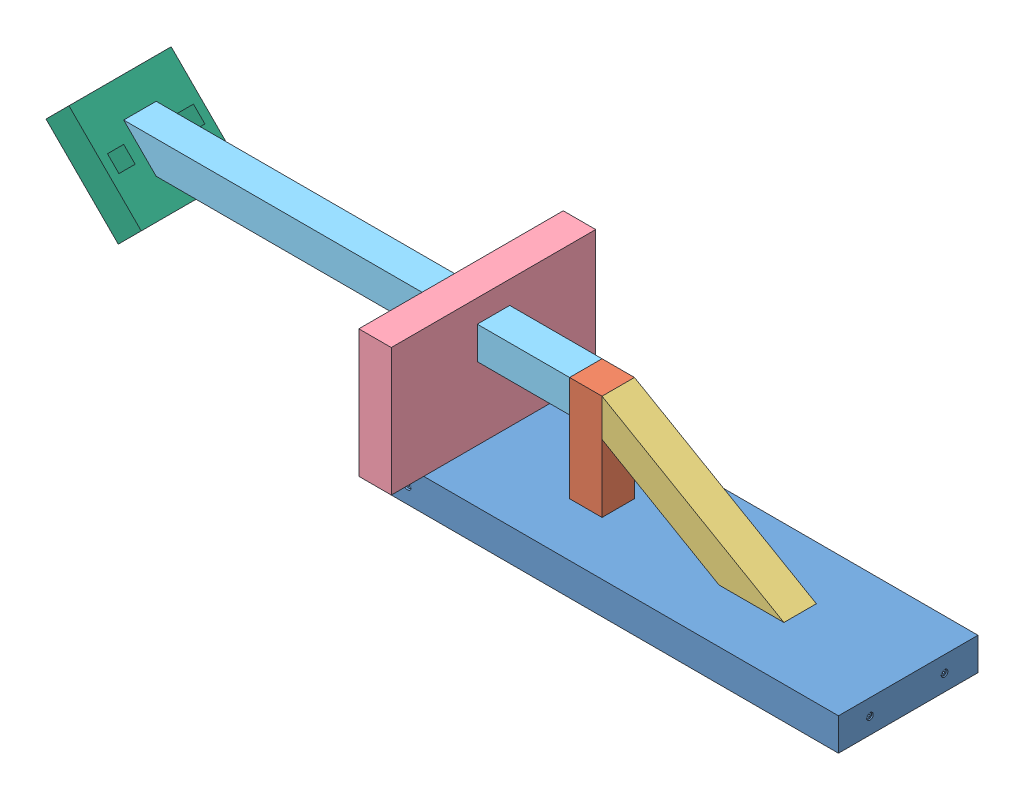
SolidWorks assembly mounting, configuration Default. Lengths in mm.
Overall size (634.84 125.4 160).
11 component instances, 7 part files, 25 mates.
Components (placement in the parent):
- small side with mount-1: small side with mount [Default] at (84.4409 129.8195 235.0864) size (350 25.4 109.2)
- a side of triangle-1: a side of triangle [Default] at (32.483 196.3149 235.0864) x (0 1 0) z (0 0 1) size (82.19 25.4 25.4)
- hypothonuse-2: hypothonuse [Default] at (174.8409 155.2195 235.0864) x (0 0 1) z (0 -1 0) size (25.4 142.36 82.19)
- antenna protector with mount-1: antenna protector with mount [Default] at (-90.5591 205.2195 235.0864) x (0 -1 0) z (0 0 1) size (100 25.4 160)
- tall mount-1: tall mount [Default] at (-167.402 224.7099 235.0864) x (0 -1 0) z (0 0 -1) size (25.4 348.97 25.4)
- mount top-1: mount top [Default] at (-329.154 224.6769 235.0844) x (0 0 1) z (0.707107 -0.707107 0) size (80 25.4 80)
- 90031A117_PHILLIPS FLAT HEAD SCREWS FOR WOOD-1: 90031A117_PHILLIPS FLAT HEAD SCREWS FOR WOOD [90031A117] at (-335.8892 217.9417 235.0844) x (0.707107 0.707107 0) z (0 0 1) size (31.75 5.71 5.71)
- 90031A117_PHILLIPS FLAT HEAD SCREWS FOR WOOD-2: 90031A117_PHILLIPS FLAT HEAD SCREWS FOR WOOD [90031A117] at (19.6301 145.6945 235.0326) x (0 1 0) z (-0.546944 0 0.837169) size (31.75 5.71 5.71)
- 90031A117_PHILLIPS FLAT HEAD SCREWS FOR WOOD-3: 90031A117_PHILLIPS FLAT HEAD SCREWS FOR WOOD [90031A117] at (149.6575 145.6945 235.1226) x (0 1 0) z (-0.546944 0 0.837169) size (31.75 5.71 5.71)
- 90031A117_PHILLIPS FLAT HEAD SCREWS FOR WOOD-6: 90031A117_PHILLIPS FLAT HEAD SCREWS FOR WOOD [90031A117] at (-77.8591 145.6945 264.2864) x (0 1 0) z (-0.546944 0 0.837169) size (31.75 5.71 5.71)
- 90031A117_PHILLIPS FLAT HEAD SCREWS FOR WOOD-7: 90031A117_PHILLIPS FLAT HEAD SCREWS FOR WOOD [90031A117] at (-77.8591 145.6945 205.8864) x (0 1 0) z (-0.546944 0 0.837169) size (31.75 5.71 5.71)
Mates (geometry in assembly coordinates):
- Concentric4: concentric aligned: cylinder of small side with mount-1 through (149.4409 129.8195 235.0864) axis (0 -1 0) radius 0.889; cylinder of hypothonuse-2 through (149.4409 155.2195 235.0864) axis (0 -1 0) radius 0.5956
- Coincident6: coincident anti-aligned: plane of small side with mount-1 through (84.4409 155.2195 235.0864) normal (0 1 0); plane of hypothonuse-2 through (174.8409 155.2195 247.7864) normal (0 -1 0)
- Parallel5: parallel aligned: plane of small side with mount-1 through (-90.5591 155.2195 180.4864) normal (-1 0 0); plane of hypothonuse-2 through (32.483 208.0805 247.7864) normal (-1 0 0)
- Coincident7: coincident aligned: line of a side of triangle-1 through (32.483 237.4099 247.7864) axis (0 0 -1); line of hypothonuse-2 through (32.483 237.4099 247.7864) axis (0 0 -1)
- Coincident8: coincident aligned: plane of a side of triangle-1 through (7.083 155.2199 222.3864) normal (0 0 -1); plane of hypothonuse-2 through (174.8409 155.2195 222.3864) normal (0 0 -1)
- Coincident9: coincident aligned: plane of a side of triangle-1 through (7.083 155.2199 247.7864) normal (0 0 1); plane of hypothonuse-2 through (174.8409 155.2195 247.7864) normal (0 0 1)
- Coincident10: coincident anti-aligned: plane of a side of triangle-1 through (32.483 196.3149 235.0864) normal (1 0 0); plane of hypothonuse-2 through (32.483 208.0805 247.7864) normal (-1 0 0)
- Coincident12: coincident anti-aligned: plane of small side with mount-1 through (84.4409 155.2195 235.0864) normal (0 1 0); plane of antenna protector with mount-1 through (-65.1591 155.2195 155.0864) normal (0 -1 0)
- Coincident13: coincident aligned: line of a side of triangle-1 through (7.083 237.4099 222.3864) axis (0 -1 0); line of tall mount-1 through (7.083 237.4099 222.3864) axis (0 -1 0)
- Coincident14: coincident aligned: line of a side of triangle-1 through (7.083 155.2199 247.7864) axis (0 1 0); line of tall mount-1 through (7.083 212.0099 247.7864) axis (0 1 0)
- Coincident15: coincident aligned: line of a side of triangle-1 through (7.083 237.4099 247.7864) axis (0 0 -1); line of tall mount-1 through (7.083 237.4099 247.7864) axis (0 0 -1)
- Tangent4: tangent: curve of tall mount-1; circle of mount top-1
- Parallel15: parallel aligned: plane of tall mount-1 through (-341.887 237.4099 247.7864) normal (0 0 1); plane of mount top-1 through (-375.3988 235.0007 275.0844) normal (0 0 1)
- Parallel16: parallel aligned: plane of tall mount-1 through (-341.887 237.4099 222.3864) normal (0 0 -1); plane of mount top-1 through (-375.3988 235.0007 195.0844) normal (0 0 -1)
- Coincident31: coincident aligned: plane of mount top-1 through (-347.1145 206.7164 235.0844) normal (-0.707107 -0.707107 0); plane of 90031A117_PHILLIPS FLAT HEAD SCREWS FOR WOOD-1 through (-347.1145 206.7164 235.0844) normal (-0.707107 -0.707107 0)
- Coincident32: coincident aligned: circle of small side with mount-1; plane of 90031A117_PHILLIPS FLAT HEAD SCREWS FOR WOOD-2 through (19.6301 129.8195 235.0326) normal (0 -1 0)
- Coincident33: coincident aligned: plane of small side with mount-1 through (84.4409 129.8195 235.0864) normal (0 -1 0); plane of 90031A117_PHILLIPS FLAT HEAD SCREWS FOR WOOD-2 through (19.6301 129.8195 235.0326) normal (0 -1 0)
- Coincident34: coincident aligned: circle of small side with mount-1; plane of 90031A117_PHILLIPS FLAT HEAD SCREWS FOR WOOD-3 through (149.6575 129.8195 235.1226) normal (0 -1 0)
- Concentric16: concentric aligned: cylinder of small side with mount-1 through (-77.8591 129.8195 264.2864) axis (0 -1 0) radius 0.889; cylinder of 90031A117_PHILLIPS FLAT HEAD SCREWS FOR WOOD-6 through (-77.8591 129.8195 264.2864) axis (0 -1 0) radius 1.4224
- Coincident39: coincident aligned: plane of small side with mount-1 through (84.4409 129.8195 235.0864) normal (0 -1 0); plane of 90031A117_PHILLIPS FLAT HEAD SCREWS FOR WOOD-6 through (-77.8591 129.8195 264.2864) normal (0 -1 0)
- Concentric17: concentric aligned: cylinder of small side with mount-1 through (-77.8591 129.8195 205.8864) axis (0 -1 0) radius 0.889; cylinder of 90031A117_PHILLIPS FLAT HEAD SCREWS FOR WOOD-7 through (-77.8591 129.8195 205.8864) axis (0 -1 0) radius 1.4224
- Coincident40: coincident aligned: plane of small side with mount-1 through (84.4409 129.8195 235.0864) normal (0 -1 0); plane of 90031A117_PHILLIPS FLAT HEAD SCREWS FOR WOOD-7 through (-77.8591 129.8195 205.8864) normal (0 -1 0)
- Coincident41: coincident anti-aligned: line of small side with mount-1 through (-90.5591 155.2195 180.4864) axis (0 0 1); line of antenna protector with mount-1 through (-90.5591 155.2195 315.0864) axis (0 0 -1)
- Coincident43: coincident anti-aligned: plane of tall mount-1 through (-341.887 237.4099 247.7864) normal (-0.707107 -0.707107 0); plane of mount top-1 through (-329.154 224.6769 235.0844) normal (0.707107 0.707107 0)
- Concentric18: concentric aligned: cone of mount top-1 through (-347.1145 206.7164 235.0844) axis (0.707107 0.707107 0); cone of 90031A117_PHILLIPS FLAT HEAD SCREWS FOR WOOD-1 through (-345.9112 207.9197 235.0844) axis (0.707107 0.707107 0)
